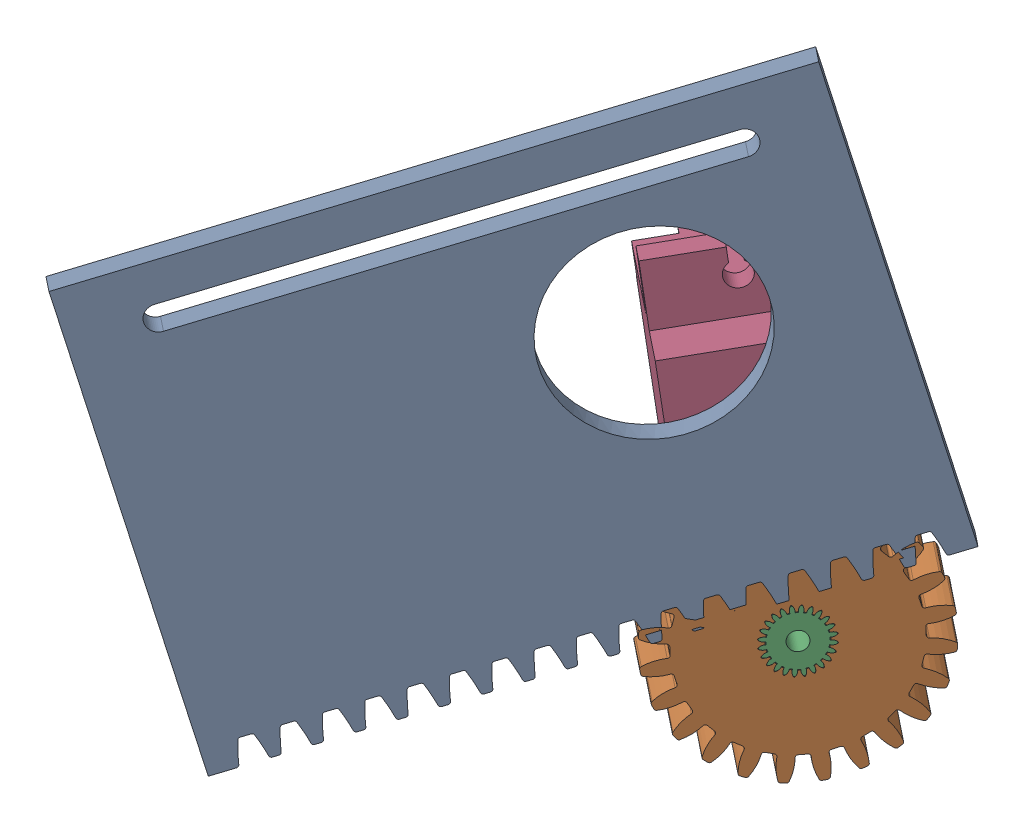
SolidWorks assembly Dropdown mechanism, configuration Default. Lengths in mm.
Overall size (41.31 55.25 55.07).
4 component instances, 4 part files, 6 mates.
Components (placement in the parent):
- Magazine door-1: Magazine door [Default] at (2.3454 -12.3389 30.5879) x (-0.763567 -0.126919 -0.633133) z (0.589613 0.262754 -0.763752) size (2 36 50)
- Gear-1: Gear [Default] at (1.567 -21.2344 26.9921) x (0.115103 -0.991543 0.05995) z (-0.635388 -0.0271 0.771718) size (19.87 4 19.87)
- PZ2-1: PZ2 [Predeterminado] at (4.6213 -20.7267 29.5247) x (0.242489 -0.965091 -0.098982) z (-0.598469 -0.229108 0.767688) size (4.99 10 4.99)
- Pieza1-1: Pieza1 [Predeterminado] at (-16.4765 -19.1655 12.8006) x (0.172655 -0.984923 -0.010786) z (-0.622219 -0.117549 0.773968) size (32 21.5 12)
Mates (geometry in assembly coordinates):
- Concentric1: concentric aligned: cylinder of Gear-1 through (-3.0144 -21.9959 23.1933) axis (0.763567 0.126919 0.633133) radius 2.55; cylinder of PZ2-1 through (-3.0144 -21.9959 23.1933) axis (0.763567 0.126919 0.633133) radius 0.75
- GearMate3: gear = 1 : 1 mm: cylinder of PZ2-1 through (-1.8945 -20.9721 21.6374) axis (0.763567 0.126919 0.633133) radius 0.5823; cylinder of Gear-1 through (2.7165 -20.2659 25.4116) axis (0.763567 0.126919 0.633133) radius 0.65
- Coincident3: coincident aligned: plane of Gear-1 through (4.6213 -20.7267 29.5247) normal (0.763567 0.126919 0.633133); plane of PZ2-1 through (4.6213 -20.7267 29.5247) normal (0.763567 0.126919 0.633133)
- Coincident4: coincident anti-aligned: plane of PZ2-1 through (-3.0144 -21.9959 23.1933) normal (-0.763567 -0.126919 -0.633133); plane of Pieza1-1 through (-3.0144 -21.9959 23.1933) normal (0.763567 0.126919 0.633133)
- Concentric3: concentric aligned: cylinder of PZ2-1 through (-3.0144 -21.9959 23.1933) axis (0.763567 0.126919 0.633133) radius 0.75; cylinder of Pieza1-1 through (-3.0144 -21.9959 23.1933) axis (0.763567 0.126919 0.633133) radius 2.5
- Coincident5: coincident aligned: plane of Magazine door-1 through (2.3454 -12.3389 30.5879) normal (0.763567 0.126919 0.633133); plane of Gear-1 through (4.6213 -20.7267 29.5247) normal (0.763567 0.126919 0.633133)
